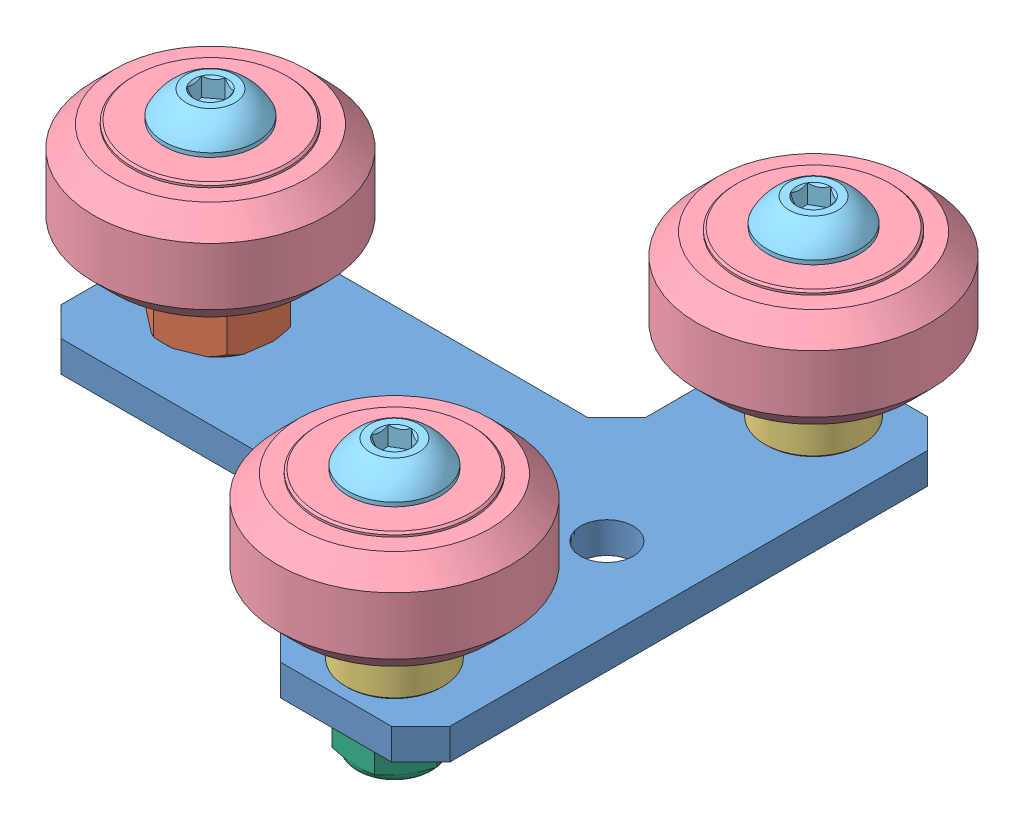
SolidWorks assembly X-102, configuration Default. Lengths in mm.
Overall size (65.73 28.3 66.9).
13 component instances, 6 part files, 24 mates.
Components (placement in the parent):
- X-002_rB-1: X-002_rB [Default] at (-20.7152 31.941 58.3018) size (57.4 3.17 55)
- H-002-1: H-002 [Default] at (-11.7152 35.116 48.3018) x (-0.137617 0 0.990486) z (-0.990486 0 -0.137617) size (11.55 8.5 10)
- H-003-1: H-003 [Default] at (27.9848 35.116 26.8018) x (1 0 0) z (0 1 0) size (10 10 6)
- H-003-2: H-003 [Default] at (27.9848 35.116 69.8018) x (-1 0 0) z (0 1 0) size (10 10 6)
- H-014-1: H-014 [Default] at (-12.4976 46.616 48.1931) x (0 -1 0) z (0.120459 0 0.992718) size (11 23.9 23.9)
- H-014-2: H-014 [Default] at (27.9848 46.616 26.8018) x (0 -1 0) z (0 0 1) size (11 23.9 23.9)
- H-014-3: H-014 [Default] at (27.9848 46.616 69.8018) x (0 -1 0) z (0 0 1) size (11 23.9 23.9)
- H-009-1: H-009 [91239A234] at (27.9848 54.866 69.8018) x (1 0 0) z (0 1 0) size (9.5 9.5 28.3)
- H-012-1: H-012 [90576A104] at (27.9848 31.941 69.8018) x (-0.837169 0 -0.546944) z (-0.546944 0 0.837169) size (8 5.15 9.24)
- H-009-2: H-009 [91239A234] at (-12.4976 54.866 48.1931) x (0.992718 0 -0.120459) z (0 1 0) size (9.5 9.5 28.3)
- H-009-3: H-009 [91239A234] at (27.9848 54.866 26.8018) x (1 0 0) z (0 1 0) size (9.5 9.5 28.3)
- H-012-2: H-012 [90576A104] at (-12.4976 31.941 48.1931) x (-0.896957 0 -0.442117) z (-0.442117 0 0.896957) size (8 5.15 9.24)
- H-012-3: H-012 [90576A104] at (27.9848 31.941 26.8018) x (-0.837169 0 -0.546944) z (-0.546944 0 0.837169) size (8 5.15 9.24)
Mates (geometry in assembly coordinates):
- Concentric2: concentric anti-aligned: circle of X-002_rB-1; circle of H-003-2
- Coincident2: coincident anti-aligned: plane of X-002_rB-1 through (-20.7152 35.116 58.3018) normal (0 1 0); plane of H-003-2 through (25.2348 35.116 69.8018) normal (0 -1 0)
- Concentric3: concentric anti-aligned: circle of X-002_rB-1; circle of H-003-1
- Coincident3: coincident anti-aligned: plane of X-002_rB-1 through (-20.7152 35.116 58.3018) normal (0 1 0); plane of H-003-1 through (30.7348 35.116 26.8018) normal (0 -1 0)
- Concentric4: concentric anti-aligned: circle of H-003-1; circle of H-014-2
- Coincident4: coincident anti-aligned: plane of H-003-1 through (32.7848 41.116 26.8018) normal (0 1 0); plane of H-014-2 through (27.9848 41.116 26.8018) normal (0 -1 0)
- Concentric6: concentric anti-aligned: circle of H-003-2; circle of H-014-3
- Coincident6: coincident anti-aligned: plane of H-003-2 through (23.1848 41.116 69.8018) normal (0 1 0); plane of H-014-3 through (27.9848 41.116 69.8018) normal (0 -1 0)
- Concentric10: concentric anti-aligned: circle of H-014-3; circle of H-009-1
- Coincident10: coincident anti-aligned: plane of H-014-3 through (27.9848 52.116 69.8018) normal (0 1 0); plane of H-009-1 through (27.9848 52.116 74.5518) normal (0 -1 0)
- Coincident11: coincident anti-aligned: plane of X-002_rB-1 through (-20.7152 31.941 58.3018) normal (0 -1 0); plane of H-012-1 through (35.1229 31.941 66.1895) normal (0 1 0)
- Concentric11: concentric aligned: circle of X-002_rB-1; circle of H-012-1
- Concentric14: concentric aligned: circle of X-002_rB-1; circle of H-012-3
- Concentric15: concentric anti-aligned: circle of H-003-1; circle of H-009-3
- Coincident12: coincident anti-aligned: plane of H-014-2 through (27.9848 52.116 26.8018) normal (0 1 0); plane of H-009-3 through (27.9848 52.116 31.5518) normal (0 -1 0)
- Coincident13: coincident anti-aligned: plane of H-014-1 through (-12.4976 52.116 48.1931) normal (0 1 0); plane of H-009-2 through (-11.9255 52.116 52.9085) normal (0 -1 0)
- Coincident14: coincident anti-aligned: plane of X-002_rB-1 through (-20.7152 31.941 58.3018) normal (0 -1 0); plane of H-012-3 through (35.1229 31.941 23.1895) normal (0 1 0)
- Coincident15: coincident anti-aligned: plane of X-002_rB-1 through (-20.7152 31.941 58.3018) normal (0 -1 0); plane of H-012-2 through (-5.8467 31.941 43.7473) normal (0 1 0)
- Concentric16: concentric anti-aligned: cylinder of X-002_rB-1 through (-11.7152 35.116 48.3018) axis (0 -1 0) radius 3.56; cylinder of H-002-1 through (-11.7152 32.616 48.3018) axis (0 1 0) radius 3.555
- Coincident16: coincident anti-aligned: plane of X-002_rB-1 through (-20.7152 35.116 58.3018) normal (0 1 0); plane of H-002-1 through (-11.7152 35.116 48.3018) normal (0 -1 0)
- Concentric17: concentric anti-aligned: circle of H-014-1; circle of H-009-2
- Concentric18: concentric anti-aligned: circle of H-002-1; circle of H-014-1
- Coincident17: coincident anti-aligned: plane of H-002-1 through (-11.7152 41.116 48.3018) normal (0 1 0); plane of H-014-1 through (-12.4976 41.116 48.1931) normal (0 -1 0)
- Concentric19: concentric anti-aligned: circle of H-009-2; circle of H-012-2
